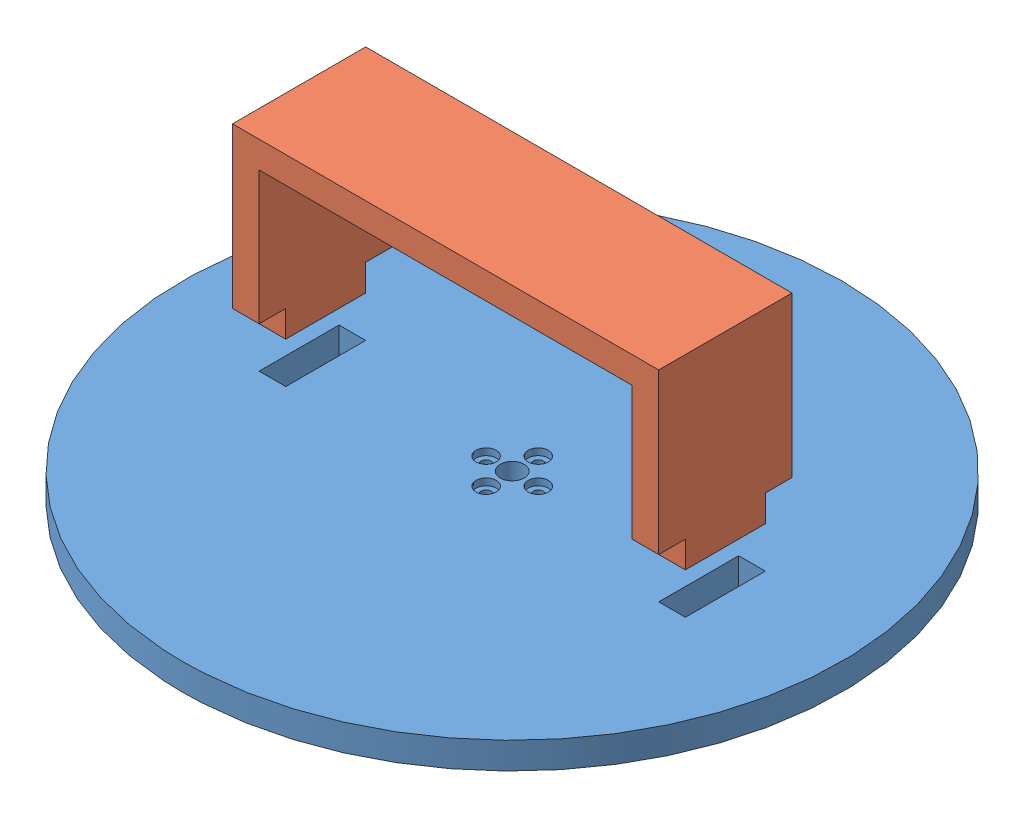
SolidWorks assembly scaled_platform_assembly, configuration Default. Lengths in mm.
Overall size (247.5 95.4 247.5).
2 component instances, 2 part files, 6 mates.
Components (placement in the parent):
- Scaled_Platform_baseOnly-1: Scaled_Platform_baseOnly [Default] at origin size (247.5 10 247.5)
- scaled_platform_bridgeOnly-1: scaled_platform_bridgeOnly [Default] at (0 95.4 0) x (1 0 0) z (0 0 -1) size (160 70 50)
Mates (geometry in assembly coordinates):
- Parallel1: parallel aligned: plane of scaled_platform_bridgeOnly-1 through (80 85.4 25) normal (0 0 1)
- Parallel2: parallel aligned: plane of scaled_platform_bridgeOnly-1 through (0 95.4 0) normal (0 1 0)
- Parallel3: parallel aligned: plane of scaled_platform_bridgeOnly-1 through (80 85.4 -25) normal (1 0 0)
- Coincident4: coincident anti-aligned: plane of Scaled_Platform_baseOnly-1 through (-80 0 15) normal (1 0 0); plane of scaled_platform_bridgeOnly-1 through (-80 85.4 -25) normal (-1 0 0)
- Coincident5: coincident anti-aligned: plane of Scaled_Platform_baseOnly-1 through (-80 0 -15) normal (0 0 1); plane of scaled_platform_bridgeOnly-1 through (-70 25.4 -15) normal (0 0 -1)
- LimitDistance1: limit distance = 25.4 mm aligned: plane of scaled_platform_bridgeOnly-1 through (0 25.4 0) normal (0 -1 0); plane of Scaled_Platform_baseOnly-1 through (0 0 0) normal (0 -1 0)
